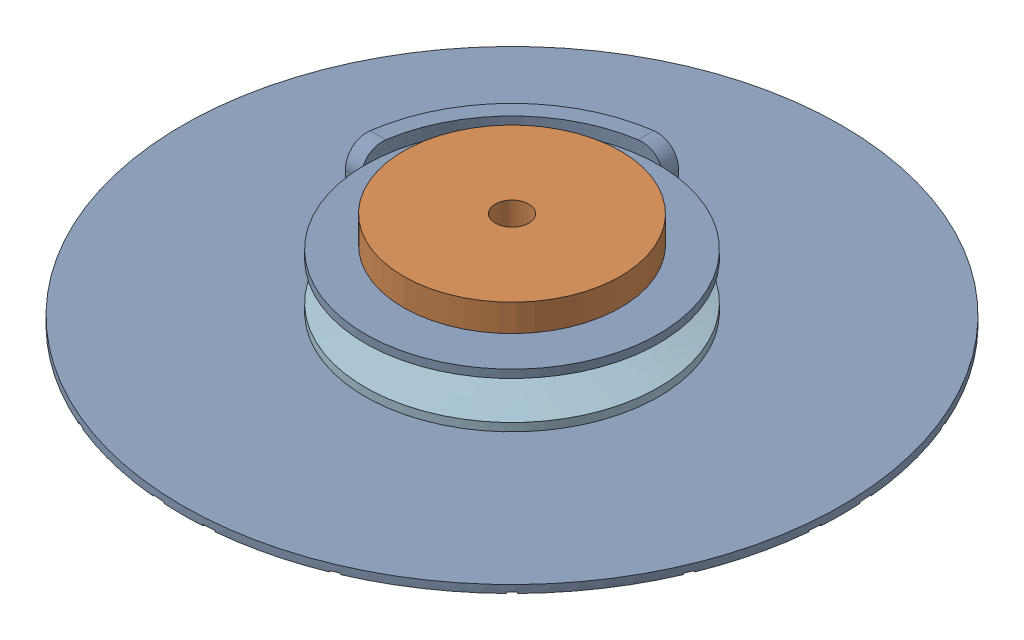
SolidWorks assembly pully assem, configuration Default. Lengths in mm.
Overall size (85 12.38 85).
5 component instances, 4 part files, 8 mates.
Components (placement in the parent):
- 1 string pully v3-1: 1 string pully v3 [Default] at (5.758 11.8533 21.7539) size (85 9.5 85)
- 5972K91_Ball Bearing-1: 5972K91_Ball Bearing [5972K91] at (5.758 16.7333 21.7539) x (-0.738185 0 -0.674598) z (0 -1 0) size (22 22 7)
- pully press fit guide-1: pully press fit guide [Default] at (5.758 13.2333 21.7539) x (-0.837169 0 -0.546944) z (0 -1 0) size (37.83 37.83 3)
- pully press fit guide-3: pully press fit guide [Default] at (5.758 20.2333 21.7539) x (-1 0 0) z (0 1 0) size (37.83 37.83 3)
- bearing holder-1: bearing holder [Default] at (5.758 20.2333 21.7539) size (28 4 28)
Mates (geometry in assembly coordinates):
- Concentric1: concentric anti-aligned: circle of 1 string pully v3-1; cylinder of 5972K91_Ball Bearing-1 through (5.758 13.2333 21.7539) axis (0 -1 0) radius 11
- Coincident1: coincident anti-aligned: plane of 1 string pully v3-1 through (5.758 13.2333 21.7539) normal (0 1 0); plane of 5972K91_Ball Bearing-1 through (8.6925 13.2333 18.5428) normal (0 -1 0)
- Coincident2: coincident aligned: plane of 5972K91_Ball Bearing-1 through (8.6925 13.2333 18.5428) normal (0 -1 0); plane of pully press fit guide-1 through (15.0338 13.2333 27.814) normal (0 -1 0)
- Concentric2: concentric aligned: cylinder of 5972K91_Ball Bearing-1 through (5.758 13.2333 21.7539) axis (0 -1 0) radius 11; cylinder of pully press fit guide-1 through (5.758 13.2333 21.7539) axis (0 -1 0) radius 11.08
- Concentric3: concentric anti-aligned: cylinder of 5972K91_Ball Bearing-1 through (5.758 13.2333 21.7539) axis (0 -1 0) radius 4; cylinder of pully press fit guide-3 through (5.758 20.2333 21.7539) axis (0 1 0) radius 11.08
- Coincident4: coincident aligned: plane of 5972K91_Ball Bearing-1 through (12.9425 20.2333 13.8922) normal (0 1 0); plane of pully press fit guide-3 through (16.838 20.2333 21.7539) normal (0 1 0)
- Coincident5: coincident anti-aligned: plane of 5972K91_Ball Bearing-1 through (8.6925 20.2333 18.5428) normal (0 1 0); plane of bearing holder-1 through (5.758 20.2333 21.7539) normal (0 -1 0)
- Concentric4: concentric anti-aligned: circle of pully press fit guide-3; cylinder of bearing holder-1 through (5.758 24.2333 21.7539) axis (0 -1 0) radius 14
